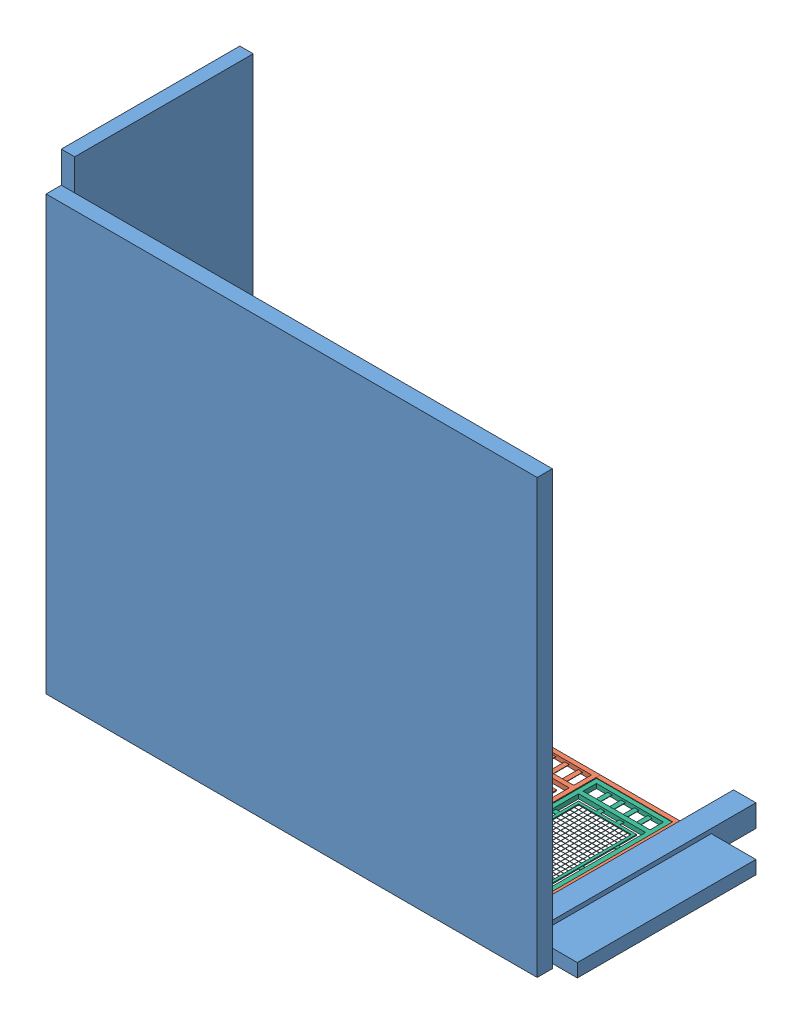
SolidWorks assembly Assemblage, configuration Défaut. Lengths in mm.
Overall size (5780 5200 2670).
6 component instances, 6 part files, 22 mates.
Components (placement in the parent):
- SUPPORT-1: SUPPORT [Défaut] at (-3167.623 -909.2815 1193.7566) size (5780 5200 2670)
- PORTAIL-2: PORTAIL [Défaut<Brut d'usinage>] at (-2907.623 -739.2815 -1135.2434) size (4510 50 2250)
- Support moteur-1: Support moteur [Défaut] at (-2907.623 -689.2815 -1135.2434) x (-1 0 0) z (0 1 0) size (500 51 234)
- Moteur-1: Moteur [Défaut] at (518.0081 1772.0646 956.5028) x (0 0 1) z (1 0 0) size (100 100 290)
- Pneu-2: Pneu [Défaut] at (668.0081 -507.2863 1059.1761) x (-1 0 0) z (0 -0.916093 0.400965) size (75.01 260 260)
- Portillon-1: Portillon [Défaut] at (702.377 -739.2815 -680.2434) x (1 0 0) z (0 -1 0) size (850 1790 50)
Mates (geometry in assembly coordinates):
- Coaxiale1: concentric: cylinder of SUPPORT-1 through (-2867.623 -714.2815 -1060.2434) axis (0 0 1) radius 17.5; cylinder of PORTAIL-2 through (-2867.623 -714.2815 -1060.2434) axis (0 0 1) radius 17.5
- Coaxiale2: concentric: cylinder of SUPPORT-1 through (-2867.623 -714.2815 1164.7566) axis (0 0 1) radius 17.5; cylinder of PORTAIL-2 through (-2867.623 -714.2815 1189.7566) axis (0 0 -1) radius 17.5
- Coïncidente1: coincident: plane of SUPPORT-1 through (-2917.623 -754.2815 1189.7566) normal (0 0 -1); plane of PORTAIL-2 through (-2867.623 -714.2815 1189.7566) normal (0 0 1)
- AngleLimite3: limit planar angle = 3.141593 rad: plane of SUPPORT-1 through (1609.377 -739.2815 -306.2434) normal (0 1 0); plane of PORTAIL-2 through (642.377 -739.2815 -805.9541) normal (0 -1 0)
- Sur place1: in place: plane of PORTAIL-2 through (642.377 -689.2815 -805.9541) normal (0 1 0); plane of ? through (0 -689.2815 0) normal (0 1 0); moOrthogonalPlaneRef_w of PORTAIL-2 through (642.377 -689.2815 -805.9541) normal (0 1 0); unknown of ?; plane of PORTAIL-2 through (642.377 -689.2815 -805.9541) normal (0 1 0); line of ? through (-55 0 -689.2815) axis (0 -1 0); plane of PORTAIL-2 through (642.377 -689.2815 -805.9541) normal (0 1 0); unknown of Support moteur-1
- Coïncidente2: coincident: plane of PORTAIL-2; plane of Support moteur-1
- Coïncidente3: coincident: moOrthogonalPlaneRef_w of PORTAIL-2 through (-2907.623 -689.2815 -1135.2434) normal (0 0 1); plane of Support moteur-1
- Coïncidente4: coincident: moOrthogonalPlaneRef_w of PORTAIL-2 through (-2907.623 -689.2815 -1135.2434) normal (1 0 0); plane of Support moteur-1
- Parallèle3: parallel: plane of PORTAIL-2 through (692.377 -689.2815 -805.9541) normal (1 0 0); plane of Moteur-1 through (598.0081 -555.2815 1113.7566) normal (1 0 0)
- Perpendiculaire2: perpendicular: plane of PORTAIL-2 through (642.377 -689.2815 -805.9541) normal (0 1 0); plane of Moteur-1 through (598.0081 -455.2815 1013.7566) normal (0 0 -1)
- Coïncidente17: coincident: plane of Support moteur-1 through (192.377 -455.2815 1155.7566) normal (0 1 0); plane of Moteur-1 through (598.0081 -455.2815 1113.7566) normal (0 1 0)
- Coïncidente18: coincident: plane of Support moteur-1 through (598.0081 -455.2815 1155.7566) normal (1 0 0); plane of Moteur-1 through (598.0081 -555.2815 1113.7566) normal (1 0 0)
- Coaxiale3: concentric: cylinder of Moteur-1 through (648.0081 -505.2815 1063.7566) axis (-1 0 0) radius 5; cylinder of Pneu-2 through (695.0895 -505.2815 1063.7566) axis (1 0 0) radius 5
- Tangent1: tangent: plane of SUPPORT-1 through (-3417.623 3940.7185 1193.7566) normal (0 0 -1); cylinder of Pneu-2 through (695.0895 -505.2815 1063.7566) axis (1 0 0) radius 130; face of SUPPORT-1; face of Pneu-2
- Distance2: distance = 20 mm: plane of Moteur-1 through (648.0081 -505.2815 1063.7566) normal (1 0 0); plane of Pneu-2 through (668.0081 -488.227 1102.7213) normal (1 0 0)
- Coïncidente19: coincident: plane of PORTAIL-2 through (1552.377 -739.2815 498864.7566) normal (-1 0 0); plane of Portillon-1 through (1552.377 -739.2815 1109.7566) normal (1 0 0)
- Parallèle4: parallel: plane of PORTAIL-2 through (1602.377 -739.2815 -685.2434) normal (0 0 1); plane of Portillon-1 through (702.377 -689.2815 -680.2434) normal (0 0 -1)
- Coïncidente21: coincident: plane of PORTAIL-2 through (1602.377 -689.2815 -735.2434) normal (0 1 0); plane of Portillon-1 through (702.377 -689.2815 1109.7566) normal (0 1 0)
- Distance3: distance = 5 mm: plane of Portillon-1 through (702.377 -689.2815 -680.2434) normal (0 0 -1); plane of PORTAIL-2 through (1602.377 -739.2815 -685.2434) normal (0 0 1); unknown of PORTAIL-2; unknown of PORTAIL-2; unknown of Moteur-1
- Vitesse1: unknown: plane of PORTAIL-2 through (642.377 -739.2815 -805.9541) normal (0 -1 0)
- Déplacement linéaire1: unknown: plane of PORTAIL-2 through (642.377 -739.2815 -805.9541) normal (0 -1 0)
- Force de réaction1: unknown = 2115.3611 mm: cylinder of SUPPORT-1 through (-2867.623 -714.2815 -1060.2434) axis (0 0 1) radius 25
